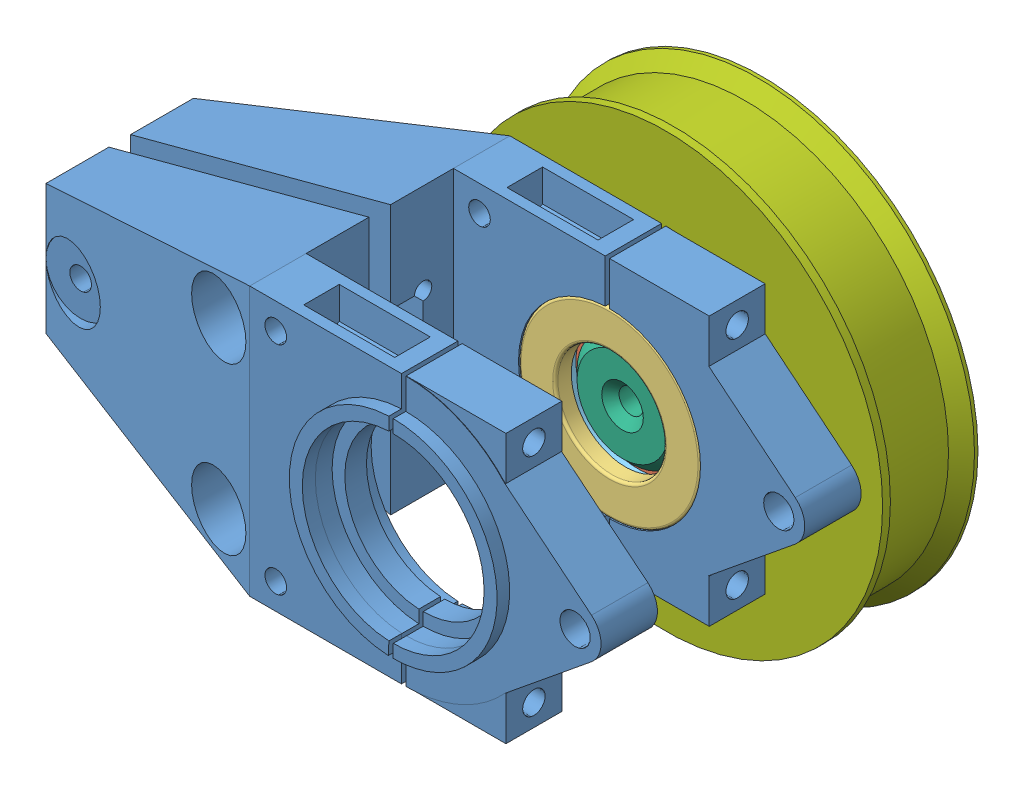
SolidWorks assembly PantherJoint, configuration Standard. Lengths in mm.
Overall size (193.5 100 91).
14 component instances, 7 part files, 16 mates.
Components (placement in the parent):
- Fork-1: Fork [Standard] at (-31 0 0) x (0 0 -1) z (0 -1 0) size (73.69 193.5 78.1)
- Fork-2: Fork [Standard] at (-31 0 0) x (0 0 1) z (0 1 0) size (73.69 193.5 78.1)
- inafag_51105_3lfplv3boirycdjq85kjesghu-1: inafag_51105_3lfplv3boirycdjq85kjesghu [Default] at (0 0 -28) x (0 0 1) z (-1 0 0) size (11 42 42)
  - inafag_51105_3lfplv3boirycdjq85kjesghu_01-1: inafag_51105_3lfplv3boirycdjq85kjesghu_01 [Default] at origin size (3.67 42 42)
  - inafag_51105_3lfplv3boirycdjq85kjesghu_02-1: inafag_51105_3lfplv3boirycdjq85kjesghu_02 [Default] at origin size (3.67 42 42)
  - inafag_51105_3lfplv3boirycdjq85kjesghu_03-1: inafag_51105_3lfplv3boirycdjq85kjesghu_03 [Default] at origin size (5.59 40.22 40.22)
  - inafag_51105_3lfplv3boirycdjq85kjesghu_04-1: inafag_51105_3lfplv3boirycdjq85kjesghu_04 [Default] at origin size (5.75 39.72 40.19)
- inafag_51105_3lfplv3boirycdjq85kjesghu-2: inafag_51105_3lfplv3boirycdjq85kjesghu [Default] at (0 0 -33) x (0 0 -1) z (-1 0 0) size (11 42 42)
  - inafag_51105_3lfplv3boirycdjq85kjesghu_01-1: inafag_51105_3lfplv3boirycdjq85kjesghu_01 [Default] at origin size (3.67 42 42)
  - inafag_51105_3lfplv3boirycdjq85kjesghu_02-1: inafag_51105_3lfplv3boirycdjq85kjesghu_02 [Default] at origin size (3.67 42 42)
  - inafag_51105_3lfplv3boirycdjq85kjesghu_03-1: inafag_51105_3lfplv3boirycdjq85kjesghu_03 [Default] at origin size (5.59 40.22 40.22)
  - inafag_51105_3lfplv3boirycdjq85kjesghu_04-1: inafag_51105_3lfplv3boirycdjq85kjesghu_04 [Default] at origin size (5.75 39.72 40.19)
- KnopM6-D25-1: KnopM6-D25 [Standard] at (0 0 -54) size (48.27 48.27 34)
- JointRing-1: JointRing [Standard] at (0 0 -30) x (1 0 0) z (0 0 -1) size (105.42 100 22)
Mates (geometry in assembly coordinates):
- Deckungsgleich5: coincident aligned: line of Fork-1 through (107.177 0 0) axis (-1 0 0); line of Fork-2 through (107.177 0 0) axis (-1 0 0)
- Deckungsgleich6: coincident anti-aligned: plane of Fork-1 through (-31 0 0) normal (0 -1 0); plane of Fork-2 through (-31 0 0) normal (0 1 0)
- Deckungsgleich7: coincident anti-aligned: line of Fork-1 through (-31 0 40.6845) axis (0 0 -1); line of Fork-2 through (-31 0 -40.6845) axis (0 0 1)
- Konzentrisch3: concentric anti-aligned: cylinder of inafag_51105_3lfplv3boirycdjq85kjesghu-1/inafag_51105_3lfplv3boirycdjq85kjesghu_01-1 through (0 0 -25.8667) axis (0 0 1) radius 21; cylinder of inafag_51105_3lfplv3boirycdjq85kjesghu-2/inafag_51105_3lfplv3boirycdjq85kjesghu_02-1 through (0 0 -41.8667) axis (0 0 -1) radius 21
- Abstand1: distance = 5 mm anti-aligned: plane of inafag_51105_3lfplv3boirycdjq85kjesghu-1/inafag_51105_3lfplv3boirycdjq85kjesghu_01-1 through (-17 0 -28) normal (0 0 -1); plane of inafag_51105_3lfplv3boirycdjq85kjesghu-2/inafag_51105_3lfplv3boirycdjq85kjesghu_01-1 through (-17 0 -33) normal (0 0 1)
- Konzentrisch7: concentric anti-aligned: cylinder of inafag_51105_3lfplv3boirycdjq85kjesghu-2/inafag_51105_3lfplv3boirycdjq85kjesghu_02-1 through (0 0 -41.8667) axis (0 0 -1) radius 21; cylinder of KnopM6-D25-1 through (0 0 -20) axis (0 0 1) radius 12.5
- Deckungsgleich19: coincident anti-aligned: plane of inafag_51105_3lfplv3boirycdjq85kjesghu-2/inafag_51105_3lfplv3boirycdjq85kjesghu_02-1 through (-16.75 0 -44) normal (0 0 -1); plane of KnopM6-D25-1 through (-24 0 -44) normal (0 0 1)
- Deckungsgleich21: coincident: point of Fork-1; point of Fork-2
- Konzentrisch8: concentric aligned: cylinder of Fork-2 through (0 0 -30) axis (0 0 1) radius 21; cylinder of inafag_51105_3lfplv3boirycdjq85kjesghu-1/inafag_51105_3lfplv3boirycdjq85kjesghu_02-1 through (0 0 -19.1333) axis (0 0 1) radius 21
- Deckungsgleich22: coincident aligned: plane of Fork-2 through (-36 31 -17) normal (0 0 1); plane of inafag_51105_3lfplv3boirycdjq85kjesghu-1/inafag_51105_3lfplv3boirycdjq85kjesghu_02-1 through (-16.75 0 -17) normal (0 0 1)
- Konzentrisch10: concentric aligned: cylinder of Fork-1 through (0 0 0) axis (0 0 -1) radius 18.0762; line of assembly
- Deckungsgleich23: coincident anti-aligned: plane of Fork-1 through (-31 0 0) normal (0 -1 0); plane of assembly through (0 0 0) normal (0 1 0)
- Deckungsgleich24: coincident anti-aligned: plane of Fork-1; plane of assembly through (0 0 0) normal (0 0 1)
- Konzentrisch11: concentric aligned: cylinder of Fork-2 through (0 0 0) axis (0 0 1) radius 23.9762; cylinder of JointRing-1 through (0 0 -50) axis (0 0 1) radius 24
- Deckungsgleich25: coincident anti-aligned: plane of Fork-2 through (0 23.9553 -30) normal (0 0 -1); plane of JointRing-1 through (0 0 -30) normal (0 0 1)
- Deckungsgleich26: coincident aligned: plane of Fork-1 through (-31 0 0) normal (0 -1 0); plane of JointRing-1 through (0 0 -30) normal (0 -1 0)
